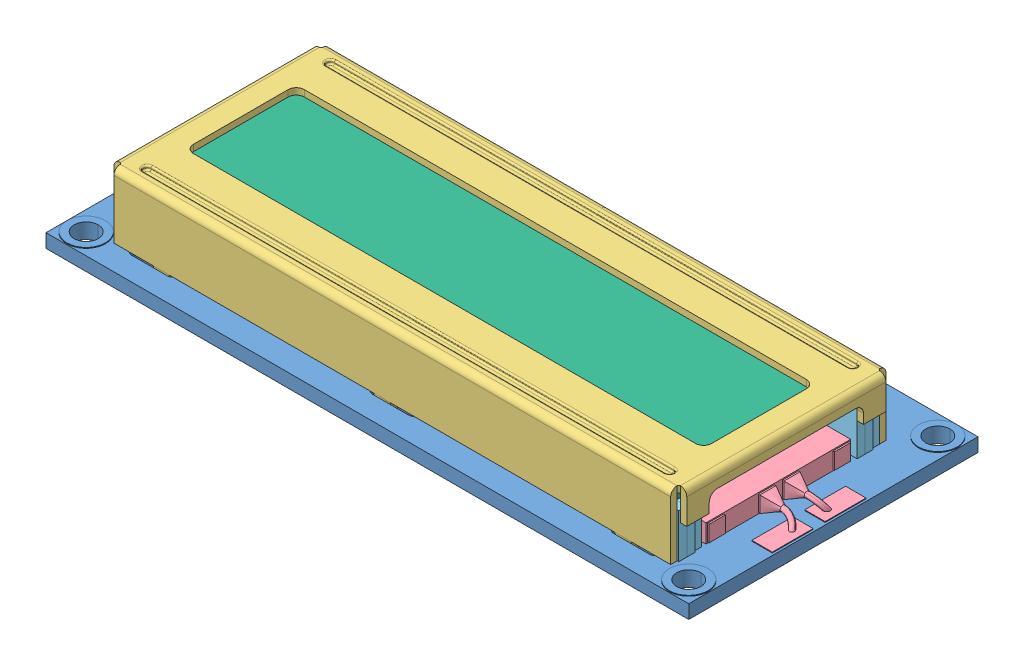
SolidWorks assembly LCD, configuration Default. Lengths in mm.
Overall size (80.01 18.33 36.01).
16 component instances, 8 part files, 0 mates.
Components (placement in the parent):
- LCD.IGS-1: LCD.IGS [Default] at origin size (80.01 18.33 36.01)
  - pcbboard.IGS-1: pcbboard.IGS [Default] at origin size (80.01 4.2 36.01)
  - 16pin_header__.IGS-1: 16pin_header__.IGS [Default] at (-32 0 -15.5) x (0 0 1) z (1 0 0) size (2.55 11.51 40.65)
  - lcd window.IGS-1: lcd window.IGS [Default] at (0 9 1.5) size (71.31 11.83 27.45)
  - backlight.IGS-1: backlight.IGS [Default] at (0 1.7 1.5) x (-1 0 0) z (0 0 -1) size (74.39 2.99 18.01)
  - conductor.IGS-1: conductor.IGS [Default] at (0 1.7 12.6) size (69.71 5.51 3.01)
  - conductor.IGS-2: conductor.IGS [Default] at (0 1.7 -9.6) size (69.71 5.51 3.01)
  - liquid crystal grabcad.IGS-1: liquid crystal grabcad.IGS [Default] at (0 7.9 1.5) size (68.51 2.21 25.01)
  - smt_resistor222.IGS-1: smt_resistor222.IGS [Default] at (-32.75 0 -5.25) x (0 0 1) z (1 0 0) size (1.91 0.66 4.11)
  - smt_resistor222.IGS-2: smt_resistor222.IGS [Default] at (-32.75 0 -2.75) x (0 0 1) z (1 0 0) size (1.91 0.66 4.11)
  - smt_resistor222.IGS-3: smt_resistor222.IGS [Default] at (-32.75 0 -0.25) x (0 0 1) z (1 0 0) size (1.91 0.66 4.11)
  - smt_resistor222.IGS-4: smt_resistor222.IGS [Default] at (-32.75 0 2.25) x (0 0 1) z (1 0 0) size (1.91 0.66 4.11)
  - smt_resistor222.IGS-5: smt_resistor222.IGS [Default] at (-32.75 0 4.75) x (0 0 1) z (1 0 0) size (1.91 0.66 4.11)
  - smt_resistor222.IGS-6: smt_resistor222.IGS [Default] at (-32.75 0 7.25) x (0 0 1) z (1 0 0) size (1.91 0.66 4.11)
  - smt_resistor101.IGS-1: smt_resistor101.IGS [Default] at (30.25 0 6.1) x (0 0 -1) z (-1 0 0) size (1.91 0.66 5.31)
  - smt_resistor101.IGS-2: smt_resistor101.IGS [Default] at (30.25 0 2.85) x (0 0 -1) z (-1 0 0) size (1.91 0.66 5.31)
